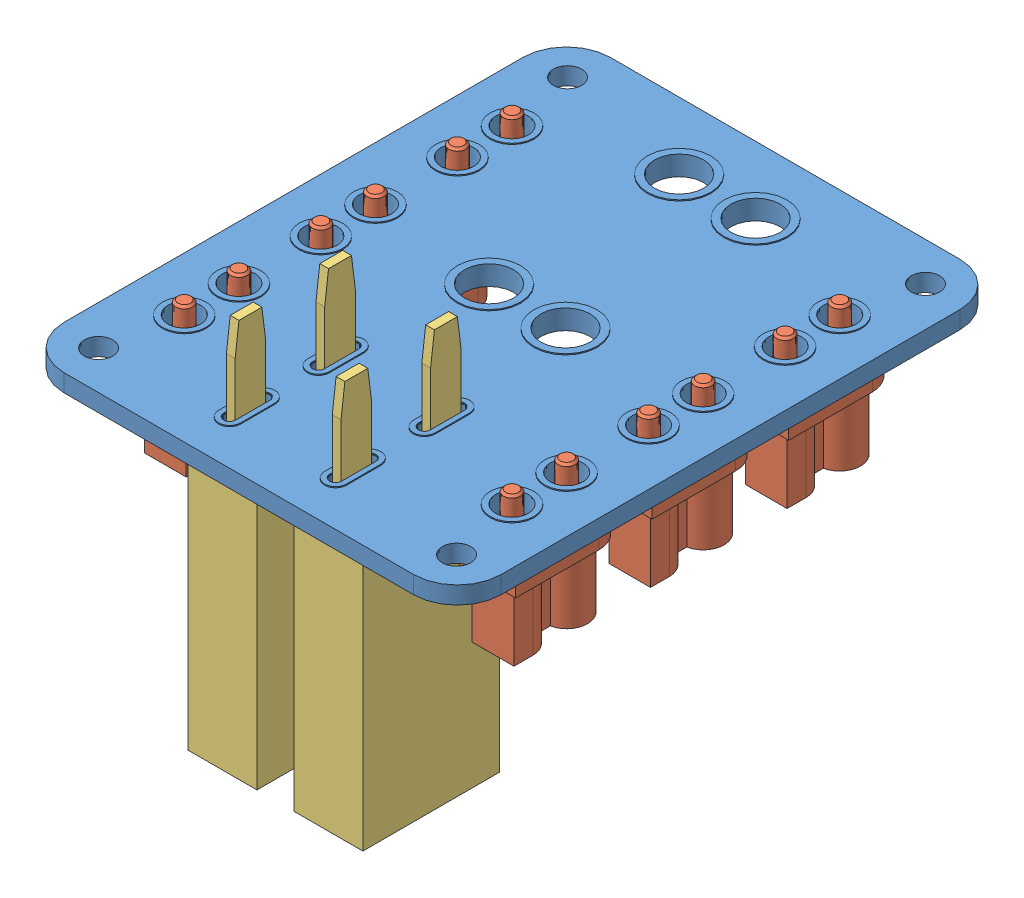
SolidWorks assembly Power Distribution Board Assembly 101, configuration Predeterminado. Lengths in mm.
Overall size (43.5 37.34 56.5).
10 component instances, 4 part files, 67 mates.
Components (placement in the parent):
- Power Distribution Board 2.0-1: Power Distribution Board 2.0 [Predeterminado] at (-3.6534 -6.8299 48) size (40 1.8 50)
- XT30 Female Connector-1: XT30 Female Connector [Predeterminado] at (11.3466 -7.6299 65.25) x (-1 0 0) z (0 -1 0) size (5.15 10.23 12.25)
- XT30 Female Connector-2: XT30 Female Connector [Predeterminado] at (11.3466 -7.6299 52.75) x (-1 0 0) z (0 -1 0) size (5.15 10.23 12.25)
- XT30 Female Connector-3: XT30 Female Connector [Predeterminado] at (11.3466 -7.6299 40.25) x (-1 0 0) z (0 -1 0) size (5.15 10.23 12.25)
- XT30 Female Connector-4: XT30 Female Connector [Predeterminado] at (-18.6534 -7.6299 65.25) x (-1 0 0) z (0 -1 0) size (5.15 10.23 12.25)
- XT30 Female Connector-5: XT30 Female Connector [Predeterminado] at (-18.6534 -7.6299 52.75) x (-1 0 0) z (0 -1 0) size (5.15 10.23 12.25)
- XT30 Female Connector-6: XT30 Female Connector [Predeterminado] at (-18.6534 -7.6299 40.25) x (-1 0 0) z (0 -1 0) size (5.15 10.23 12.25)
- Breaker 6A 28V-1: Breaker 6A 28V [Default] at (-8.5004 -20.6299 63.3981) x (0 0 1) z (1 0 0) size (12.5 35.3 6.3)
- Breaker 6A 28V-2: Breaker 6A 28V [Default] at (1.1936 -20.6299 63.3981) x (0 0 1) z (1 0 0) size (12.5 35.3 6.3)
- PCB Mount 103-1: PCB Mount 103 [Default] at (-3.6534 -2.7299 48) x (-1 0 0) z (0 -1 0) size (43.5 56.5 11.44)
Mates (geometry in assembly coordinates):
- Concéntrica1: concentric aligned: cylinder of XT90H-M body-1 through (-7.7318 16.3701 50.5703) axis (0 -1 0) radius 2.85; cylinder of XT90H-M pin-1 through (-7.7318 28.8215 50.5703) axis (0 -1 0) radius 2.85
- Concéntrica2: concentric aligned: cylinder of XT90H-M body-1 through (3.2682 16.3701 50.5703) axis (0 -1 0) radius 2.85; cylinder of XT90H-M pin-2 through (3.2682 28.8215 50.5703) axis (0 -1 0) radius 2.85
- Coincidente1: coincident anti-aligned: plane of Power Distribution Board 2.0-1 through (12.3466 -6.0299 27) normal (0 1 0); plane of XT90H-M body-1 through (-2.2318 -4.8299 50.5703) normal (0 -1 0)
- Coincidente2: coincident aligned: plane of XT90H-M pin-1 through (-7.7318 16.8215 50.5703) normal (0 -1 0); plane of XT90H-M pin-2 through (3.2682 16.8215 50.5703) normal (0 -1 0)
- Coincidente3: coincident anti-aligned: plane of Power Distribution Board 2.0-1 through (12.3466 -6.0299 27) normal (0 1 0); plane of XT90H-M SBORKA-1/XT90H-M body-1 through (-3.6534 -6.0299 54.8521) normal (0 -1 0)
- Concéntrica3: concentric: cylinder of Power Distribution Board 1.0-1 through (-3.6534 -7.6299 49.3521) axis (0 1 0) radius 3; cylinder of XT90H-M SBORKA-1/XT90H-M pin-1 through (-3.6534 0.9701 49.3521) axis (0 -1 0) radius 2.85
- Concéntrica4: concentric anti-aligned: cylinder of Power Distribution Board 2.0-1 through (-18.6534 -7.6299 33) axis (0 1 0) radius 1.5; cylinder of XT30 Male Connector-1 through (-22.6534 -4.7299 31.86) axis (0 -1 0) radius 0.775
- Concéntrica5: concentric anti-aligned: cylinder of Power Distribution Board 2.0-1 through (-18.6534 -7.6299 38) axis (0 1 0) radius 1.5; cylinder of XT30 Male Connector-1 through (-22.6534 -4.7299 36.86) axis (0 -1 0) radius 0.775
- Coincidente4: coincident anti-aligned: plane of Power Distribution Board 2.0-1 through (12.3466 -7.6299 27) normal (0 -1 0); plane of XT30 Male Connector-1 through (-22.6534 -7.6299 31.48) normal (0 1 0)
- Coincidente5: coincident anti-aligned: plane of Power Distribution Board 2.0-1 through (12.3466 -7.6299 27) normal (0 -1 0); plane of XT30 Male Connector-2 through (-22.6534 -7.6299 45.12) normal (0 1 0)
- Concéntrica6: concentric anti-aligned: cylinder of Power Distribution Board 2.0-1 through (-18.6534 -7.6299 45.5) axis (0 1 0) radius 1.5; circle of XT30 Male Connector-2
- Concéntrica7: concentric anti-aligned: cylinder of Power Distribution Board 2.0-1 through (-18.6534 -7.6299 50.5) axis (0 1 0) radius 1.5; cylinder of XT30 Male Connector-2 through (-22.6534 -4.7299 50.5) axis (0 -1 0) radius 0.775
- Concéntrica8: concentric anti-aligned: cylinder of Power Distribution Board 2.0-1 through (-18.6534 -7.6299 58) axis (0 1 0) radius 1.5; cylinder of XT30 Male Connector-3 through (-22.6534 -4.7299 59.14) axis (0 -1 0) radius 0.775
- Concéntrica9: concentric anti-aligned: cylinder of Power Distribution Board 2.0-1 through (-18.6534 -7.6299 63) axis (0 1 0) radius 1.5; cylinder of XT30 Male Connector-3 through (-22.6534 -4.7299 64.14) axis (0 -1 0) radius 0.775
- Coincidente6: coincident anti-aligned: plane of Power Distribution Board 2.0-1 through (12.3466 -7.6299 27) normal (0 -1 0); plane of XT30 Male Connector-3 through (-22.6534 -7.6299 58.76) normal (0 1 0)
- Concéntrica10: concentric anti-aligned: cylinder of Power Distribution Board 2.0-1 through (11.3466 -7.6299 58) axis (0 1 0) radius 1.5; cylinder of XT30 Male Connector-4 through (15.3466 -4.7299 59.14) axis (0 -1 0) radius 0.775
- Coincidente7: coincident anti-aligned: plane of Power Distribution Board 2.0-1 through (12.3466 -7.6299 27) normal (0 -1 0); plane of XT30 Male Connector-4 through (15.3466 -7.6299 58.76) normal (0 1 0)
- Concéntrica11: concentric anti-aligned: cylinder of Power Distribution Board 2.0-1 through (11.3466 -7.6299 63) axis (0 1 0) radius 1.5; cylinder of XT30 Male Connector-4 through (15.3466 -4.7299 64.14) axis (0 -1 0) radius 0.775
- Coincidente8: coincident anti-aligned: plane of Power Distribution Board 2.0-1 through (12.3466 -7.6299 27) normal (0 -1 0); plane of XT30 Male Connector-5 through (15.3466 -7.6299 45.12) normal (0 1 0)
- Concéntrica12: concentric anti-aligned: cylinder of Power Distribution Board 2.0-1 through (11.3466 -7.6299 45.5) axis (0 1 0) radius 1.5; cylinder of XT30 Male Connector-5 through (15.3466 -4.7299 45.5) axis (0 -1 0) radius 0.775
- Concéntrica13: concentric anti-aligned: cylinder of Power Distribution Board 2.0-1 through (11.3466 -7.6299 50.5) axis (0 1 0) radius 1.5; cylinder of XT30 Male Connector-5 through (15.3466 -4.7299 50.5) axis (0 -1 0) radius 0.775
- Coincidente9: coincident anti-aligned: plane of Power Distribution Board 2.0-1 through (12.3466 -7.6299 27) normal (0 -1 0); plane of XT30 Male Connector-6 through (15.3466 -7.6299 31.48) normal (0 1 0)
- Concéntrica14: concentric anti-aligned: cylinder of Power Distribution Board 2.0-1 through (11.3466 -7.6299 33) axis (0 1 0) radius 1.5; cylinder of XT30 Male Connector-6 through (15.3466 -4.7299 31.86) axis (0 -1 0) radius 0.775
- Concéntrica15: concentric anti-aligned: cylinder of Power Distribution Board 2.0-1 through (11.3466 -7.6299 38) axis (0 1 0) radius 1.5; cylinder of XT30 Male Connector-6 through (15.3466 -4.7299 36.86) axis (0 -1 0) radius 0.775
- Concéntrica16: concentric aligned: cylinder of Power Distribution Board 2.0-1 through (-20.0364 -7.6299 26.537) axis (0 1 0) radius 1.3; cylinder of Screw M2.5 20mm-1 through (-16.1534 -7.0299 31.35) axis (0 1 0) radius 1.25
- Concéntrica17: concentric aligned: cylinder of Power Distribution Board 2.0-1 through (12.7296 -7.6299 26.537) axis (0 1 0) radius 1.3; cylinder of Screw M2.5 20mm-4 through (8.8466 -7.0299 31.35) axis (0 1 0) radius 1.25
- Coincidente10: coincident aligned: plane of Screw M2.5 20mm-1 through (-16.1534 13.4701 31.35) normal (0 1 0); plane of Screw M2.5 20mm-4 through (8.8466 13.4701 31.35) normal (0 1 0)
- Concéntrica18: concentric aligned: cylinder of Power Distribution Board 2.0-1 through (12.7296 -7.6299 69.463) axis (0 1 0) radius 1.3; cylinder of Screw M2.5 20mm-3 through (8.8466 -7.0299 64.65) axis (0 1 0) radius 1.25
- Coincidente11: coincident aligned: plane of Screw M2.5 20mm-3 through (8.8466 13.4701 64.65) normal (0 1 0); plane of Screw M2.5 20mm-4 through (8.8466 13.4701 31.35) normal (0 1 0)
- Concéntrica19: concentric aligned: cylinder of Power Distribution Board 2.0-1 through (-20.0364 -7.6299 69.463) axis (0 1 0) radius 1.3; cylinder of Screw M2.5 20mm-2 through (-16.1534 -7.0299 64.65) axis (0 1 0) radius 1.25
- Coincidente12: coincident aligned: plane of Screw M2.5 20mm-2 through (-16.1534 13.4701 64.65) normal (0 1 0); plane of Screw M2.5 20mm-3 through (8.8466 13.4701 64.65) normal (0 1 0)
- Distancia1: distance = 17 mm anti-aligned: plane of Power Distribution Board 2.0-1 through (12.3466 -6.0299 27) normal (0 1 0); plane of Screw M2.5 20mm-3 through (8.8466 10.9701 64.65) normal (0 -1 0)
- Concéntrica20: concentric anti-aligned: cylinder of Screw M2.5 20mm-1 through (-16.1534 -7.0299 31.35) axis (0 1 0) radius 1.25; cylinder of Board Spacer 010-1 through (-16.1534 -3.0299 31.35) axis (0 -1 0) radius 1.5
- Coincidente13: coincident anti-aligned: plane of Power Distribution Board 2.0-1 through (12.3466 -6.0299 27) normal (0 1 0); plane of Board Spacer 010-1 through (-3.6534 -6.0299 47.85) normal (0 -1 0)
- Coincident1: coincident anti-aligned: plane of Power Distribution Board 2.0-1 through (12.3466 -7.6299 27) normal (0 -1 0); plane of XT30 Female Connector-1 through (11.3466 -7.6299 57.595) normal (0 1 0)
- Concentric1: concentric anti-aligned: cylinder of Power Distribution Board 2.0-1 through (11.3466 -7.6299 63) axis (0 1 0) radius 1.5; cylinder of XT30 Female Connector-1 through (11.3466 -4.7299 63) axis (0 -1 0) radius 0.775
- Concentric2: concentric anti-aligned: cylinder of Power Distribution Board 2.0-1 through (11.3466 -7.6299 58) axis (0 1 0) radius 1.5; cylinder of XT30 Female Connector-1 through (11.3466 -4.7299 58) axis (0 -1 0) radius 0.775
- Coincident2: coincident aligned: plane of XT30 Female Connector-1 through (13.9216 -10.9799 57.595) normal (1 0 0); plane of XT30 Female Connector-2 through (13.9216 -10.9799 45.095) normal (1 0 0)
- Coincident3: coincident aligned: plane of XT30 Female Connector-1 through (13.9216 -10.9799 57.595) normal (1 0 0); plane of XT30 Female Connector-3 through (13.9216 -10.9799 32.595) normal (1 0 0)
- Coincident4: coincident anti-aligned: plane of Power Distribution Board 2.0-1 through (12.3466 -7.6299 27) normal (0 -1 0); plane of XT30 Female Connector-2 through (11.3466 -7.6299 45.095) normal (0 1 0)
- Coincident5: coincident anti-aligned: plane of Power Distribution Board 2.0-1 through (12.3466 -7.6299 27) normal (0 -1 0); plane of XT30 Female Connector-3 through (11.3466 -7.6299 32.595) normal (0 1 0)
- Concentric3: concentric anti-aligned: cylinder of Power Distribution Board 2.0-1 through (11.3466 -7.6299 50.5) axis (0 1 0) radius 1.5; cylinder of XT30 Female Connector-2 through (11.3466 -4.7299 50.5) axis (0 -1 0) radius 0.775
- Concentric4: concentric anti-aligned: cylinder of Power Distribution Board 2.0-1 through (11.3466 -7.6299 38) axis (0 1 0) radius 1.5; cylinder of XT30 Female Connector-3 through (11.3466 -4.7299 38) axis (0 -1 0) radius 0.775
- Coincident6: coincident anti-aligned: plane of Power Distribution Board 2.0-1 through (12.3466 -7.6299 27) normal (0 -1 0); plane of XT30 Female Connector-4 through (-18.6534 -7.6299 57.595) normal (0 1 0)
- Coincident7: coincident anti-aligned: plane of Power Distribution Board 2.0-1 through (12.3466 -7.6299 27) normal (0 -1 0); plane of XT30 Female Connector-5 through (-18.6534 -7.6299 45.095) normal (0 1 0)
- Concentric5: concentric anti-aligned: cylinder of Power Distribution Board 2.0-1 through (-18.6534 -7.6299 50.5) axis (0 1 0) radius 1.5; cylinder of XT30 Female Connector-5 through (-18.6534 -4.7299 50.5) axis (0 -1 0) radius 0.775
- Concentric6: concentric anti-aligned: cylinder of Power Distribution Board 2.0-1 through (-18.6534 -7.6299 63) axis (0 1 0) radius 1.5; cylinder of XT30 Female Connector-4 through (-18.6534 -4.7299 63) axis (0 -1 0) radius 0.775
- Concentric7: concentric anti-aligned: cylinder of Power Distribution Board 2.0-1 through (-18.6534 -7.6299 58) axis (0 1 0) radius 1.5; cylinder of XT30 Female Connector-4 through (-18.6534 -4.7299 58) axis (0 -1 0) radius 0.775
- Coincident8: coincident aligned: plane of XT30 Female Connector-4 through (-21.2284 -10.9799 65.25) normal (-1 0 0); plane of XT30 Female Connector-5 through (-21.2284 -10.9799 52.75) normal (-1 0 0)
- Coincident9: coincident anti-aligned: plane of Power Distribution Board 2.0-1 through (12.3466 -7.6299 27) normal (0 -1 0); plane of XT30 Female Connector-6 through (-18.6534 -7.6299 32.595) normal (0 1 0)
- Coincident10: coincident aligned: plane of XT30 Female Connector-5 through (-21.2284 -10.9799 52.75) normal (-1 0 0); plane of XT30 Female Connector-6 through (-21.2284 -10.9799 40.25) normal (-1 0 0)
- Concentric8: concentric anti-aligned: cylinder of Power Distribution Board 2.0-1 through (-18.6534 -7.6299 38) axis (0 1 0) radius 1.5; cylinder of XT30 Female Connector-6 through (-18.6534 -4.7299 38) axis (0 -1 0) radius 0.775
- Concentric9: concentric anti-aligned: cylinder of Power Distribution Board 2.0-1 through (-3.6534 -7.6299 60.3521) axis (0 1 0) radius 3; cylinder of XT90H-M SBORKA-1/XT90H-M pin-2 through (-3.6534 0.9701 60.3521) axis (0 -1 0) radius 2
- Concentric10: concentric: cylinder of Power Distribution Board 2.0-1 through (-3.6534 -7.6299 60.3521) axis (0 1 0) radius 3; cylinder of XT90H-M SBORKA-2/XT90H-M pin-1 through (-3.6534 -14.6299 60.3521) axis (0 1 0) radius 2.85
- Concentric11: concentric: cylinder of Power Distribution Board 2.0-1 through (-3.6534 -7.6299 49.3521) axis (0 1 0) radius 3; cylinder of XT90H-M SBORKA-2/XT90H-M pin-2 through (-3.6534 -14.6299 49.3521) axis (0 1 0) radius 2.85
- Coincident11: coincident anti-aligned: plane of Power Distribution Board 2.0-1 through (12.3466 -7.6299 27) normal (0 -1 0); plane of XT90H-M SBORKA-2/XT90H-M body-1 through (-3.6534 -7.6299 54.8521) normal (0 1 0)
- Coincident12: coincident anti-aligned: plane of Power Distribution Board 2.0-1 through (12.3466 -7.6299 27) normal (0 -1 0); plane of Breaker 6A 28V-1 through (-5.3504 -7.6299 57.1481) normal (0 1 0)
- Coincident13: coincident anti-aligned: plane of Power Distribution Board 2.0-1 through (12.3466 -7.6299 27) normal (0 -1 0); plane of Breaker 6A 28V-2 through (4.3436 -7.6299 57.1481) normal (0 1 0)
- Coincident14: coincident aligned: plane of Breaker 6A 28V-1 through (-5.3504 -33.6299 57.1481) normal (0 0 -1); plane of Breaker 6A 28V-2 through (4.3436 -33.6299 57.1481) normal (0 0 -1)
- Width1: width aligned: plane of Breaker 6A 28V-2 through (0.7936 1.6701 68.8981) normal (-1 0 0); plane of Breaker 6A 28V-2 through (1.5936 1.6701 68.8981) normal (1 0 0); plane of Power Distribution Board 2.0-1 through (1.6936 -7.6299 68.999) normal (-1 0 0); plane of Power Distribution Board 2.0-1 through (0.6936 -7.6299 68.999) normal (1 0 0)
- Width2: width anti-aligned: plane of Breaker 6A 28V-1 through (-8.1004 1.6701 68.8981) normal (1 0 0); plane of Breaker 6A 28V-1 through (-8.9004 1.6701 68.8981) normal (-1 0 0); plane of Power Distribution Board 2.0-1 through (-8.0004 -7.6299 68.999) normal (-1 0 0); plane of Power Distribution Board 2.0-1 through (-9.0004 -7.6299 68.999) normal (1 0 0)
- Coincident15: coincident anti-aligned: plane of Power Distribution Board 2.0-1 through (12.3466 -6.0299 27) normal (0 1 0); plane of PCB Mount 100-1 through (-3.6534 -6.0299 48) normal (0 -1 0)
- Width3: width anti-aligned: plane of Power Distribution Board 2.0-1 through (-19.6534 -6.0299 73) normal (0 0 1); plane of PCB Mount 100-1 through (-19.6534 -6.0299 23) normal (0 0 -1); plane of Power Distribution Board 2.0-1 through (-23.9034 -7.7299 73.25) normal (0 0 -1); plane of PCB Mount 100-1 through (-23.9034 -7.7299 22.75) normal (0 0 1)
- Width4: width anti-aligned: plane of Power Distribution Board 2.0-1 through (16.3466 -6.0299 27) normal (1 0 0); plane of PCB Mount 100-1 through (-23.6534 -6.0299 27) normal (-1 0 0); plane of Power Distribution Board 2.0-1 through (16.5966 -7.7299 73.25) normal (-1 0 0); plane of PCB Mount 100-1 through (-23.9034 -7.7299 73.25) normal (1 0 0)
- Coincident16: coincident anti-aligned: plane of Power Distribution Board 2.0-1 through (12.3466 -6.0299 27) normal (0 1 0); plane of PCB Mount 103-1 through (-3.6534 -6.0299 48) normal (0 -1 0)
- Width5: width anti-aligned: plane of Power Distribution Board 2.0-1 through (-23.6534 -6.0299 27) normal (-1 0 0); plane of Power Distribution Board 2.0-1 through (16.3466 -6.0299 27) normal (1 0 0); plane of PCB Mount 103-1 through (-23.9034 -7.7299 22.75) normal (1 0 0); plane of PCB Mount 103-1 through (16.5966 -7.7299 22.75) normal (-1 0 0)
- Width6: width anti-aligned: plane of Power Distribution Board 2.0-1 through (-19.6534 -6.0299 73) normal (0 0 1); plane of Power Distribution Board 2.0-1 through (-19.6534 -6.0299 23) normal (0 0 -1); plane of PCB Mount 103-1 through (16.5966 -7.7299 73.25) normal (0 0 -1); plane of PCB Mount 103-1 through (16.5966 -7.7299 22.75) normal (0 0 1)
